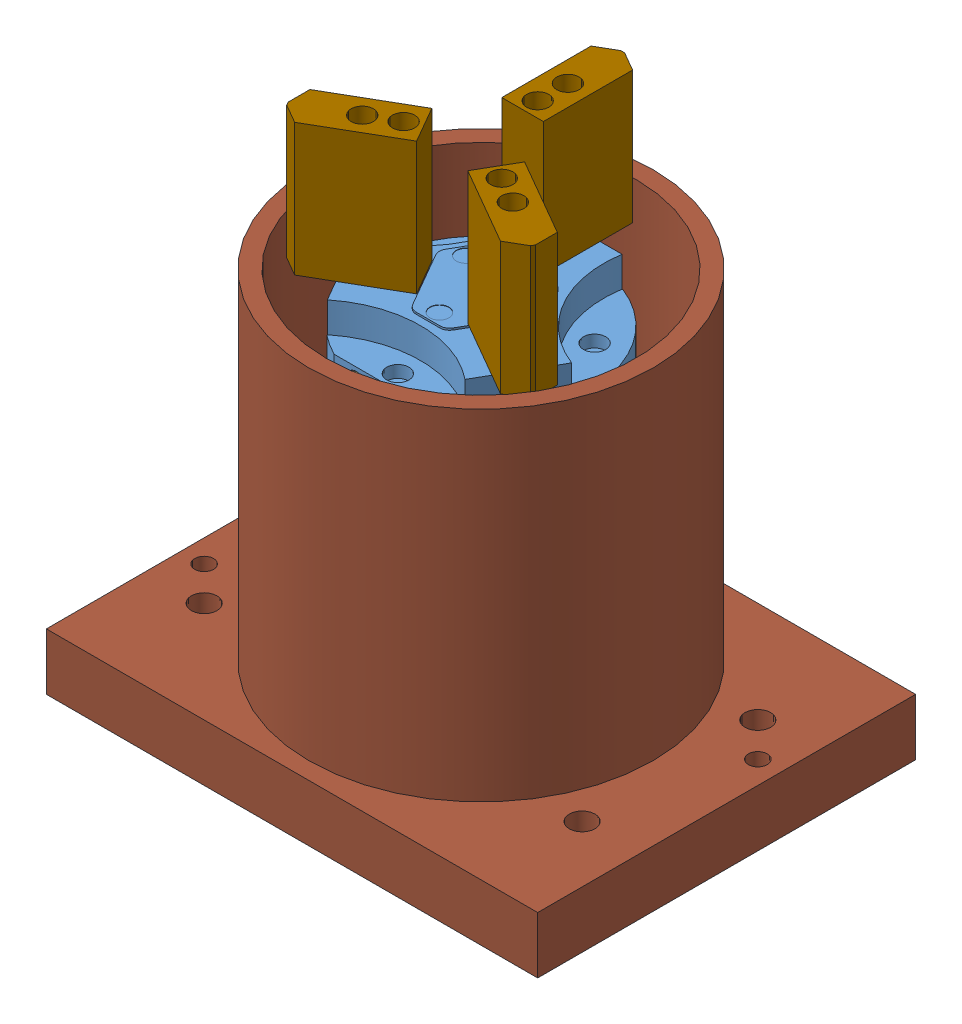
SolidWorks assembly Montagem_garra, configuration Default. Lengths in mm.
Overall size (130 138.12 100).
31 component instances, 12 part files, 72 mates.
Components (placement in the parent):
- 540862 HGDT-35-Az-1: 540862 HGDT-35-Az [Default] at origin size (58 45.5 53)
- 540862 HGDT-35-Aj-1: 540862 HGDT-35-Aj [Default] at (0 34 -2.7) x (0 0 -1) z (1 0 0) size (24.3 12 12)
- 540862 HGDT-35-Aj-2: 540862 HGDT-35-Aj [Default] at (2.3383 34 1.35) x (0.866025 0 0.5) z (-0.5 0 0.866025) size (24.3 12 12)
- 540862 HGDT-35-Aj-3: 540862 HGDT-35-Aj [Default] at (-2.3383 34 1.35) x (-0.866025 0 0.5) z (-0.5 0 -0.866025) size (24.3 12 12)
- DIN-913 - M5x5-1: DIN-913 - M5x5 [Default] at (-7 33.5 26) x (0 0 -1) z (-1 0 0) size (5.14 5 5)
- DIN-913 - M5x5-2: DIN-913 - M5x5 [Default] at (7 33.5 26) x (0 0 -1) z (-1 0 0) size (5.14 5 5)
- DIN-913 - M3x3-1: DIN-913 - M3x3 [Default] at (-7.5 0 18.5) x (0 1 0) z (-1 0 0) size (3.08 3 3)
- DIN-913 - M3x3-2: DIN-913 - M3x3 [Default] at (7.5 0 18.5) x (0 1 0) z (-1 0 0) size (3.08 3 3)
- Suporte_garra-1: Suporte_garra [Default] at (0 -10 0) x (-1 0 0) z (0 0 -1) size (85 10 85)
- parallel pin hardened_iso-1: parallel pin hardened_iso [ISO 8734 - 3 x 8 - A - St] at (-22.5 4 0) x (0 -1 0) z (-0.064733 0 -0.997903) size (8 3 3)
- parallel pin hardened_iso-2: parallel pin hardened_iso [ISO 8734 - 3 x 8 - A - St] at (22.5 4 0) x (0 -1 0) z (-0.052254 0 0.998634) size (8 3 3)
- socket head cap screw_iso-7: socket head cap screw_iso [ISO 4762 M4 x 10 - 10N] at (19.0526 -9.6 -11) x (0 1 0) z (0 0 1) size (14 7 7)
- socket head cap screw_iso-8: socket head cap screw_iso [ISO 4762 M4 x 10 - 10N] at (0 -9.6 22) x (0 1 0) z (0 0 1) size (14 7 7)
- socket head cap screw_iso-9: socket head cap screw_iso [ISO 4762 M4 x 10 - 10N] at (-19.0526 -9.6 -11) x (0 1 0) z (0 0 1) size (14 7 7)
- Centering_sleeve_8146543 ZBH-5-B-1: Centering_sleeve_8146543 ZBH-5-B [Default] at (-19.9186 47 11.5) x (0 -1 0) z (0.33337 0 0.942796) size (2.33 5 5.02)
- Centering_sleeve_8146543 ZBH-5-B-2: Centering_sleeve_8146543 ZBH-5-B [Default] at (-12.9904 47 7.5) x (0 -1 0) z (-0.239159 0 0.97098) size (2.33 5 5.02)
- Centering_sleeve_8146543 ZBH-5-B-7: Centering_sleeve_8146543 ZBH-5-B [Default] at (0 47 -23) x (0 -1 0) z (-0.800066 0 0.599912) size (2.33 5 5.02)
- Centering_sleeve_8146543 ZBH-5-B-8: Centering_sleeve_8146543 ZBH-5-B [Default] at (0 47 -15) x (0 -1 0) z (-0.813221 0 0.581954) size (2.33 5 5.02)
- Centering_sleeve_8146543 ZBH-5-B-9: Centering_sleeve_8146543 ZBH-5-B [Default] at (12.9904 47 7.5) x (0 -1 0) z (0.997447 0 -0.071406) size (2.33 5 5.02)
- Centering_sleeve_8146543 ZBH-5-B-10: Centering_sleeve_8146543 ZBH-5-B [Default] at (19.9186 47 11.5) x (0 -1 0) z (0.998302 0 0.058254) size (2.33 5 5.02)
- jaw_541102 BUB-HGDT-35---(P)-1: jaw_541102 BUB-HGDT-35---(P) [Default] at (-32.476 46 18.75) x (-0.5 0 -0.866025) z (0.866025 0 -0.5) size (11 35 26.5)
- jaw_541102 BUB-HGDT-35---(P)-2: jaw_541102 BUB-HGDT-35---(P) [Default] at (0 46 -37.5) size (11 35 26.5)
- jaw_541102 BUB-HGDT-35---(P)-3: jaw_541102 BUB-HGDT-35---(P) [Default] at (32.476 46 18.75) x (-0.5 0 0.866025) z (-0.866025 0 -0.5) size (11 35 26.5)
- socket head cap screw_din-2: socket head cap screw_din [DIN 912 M3 x 12 --- 12N] at (19.9186 55 11.5) x (0 -1 0) z (0 0 1) size (15 5.5 5.5)
- socket head cap screw_din-3: socket head cap screw_din [DIN 912 M3 x 12 --- 12N] at (12.9904 55 7.5) x (0 -1 0) z (0 0 1) size (15 5.5 5.5)
- socket head cap screw_din-4: socket head cap screw_din [DIN 912 M3 x 12 --- 12N] at (-12.9904 55 7.5) x (0 -1 0) z (0 0 1) size (15 5.5 5.5)
- socket head cap screw_din-5: socket head cap screw_din [DIN 912 M3 x 12 --- 12N] at (-19.9186 55 11.5) x (0 -1 0) z (0 0 1) size (15 5.5 5.5)
- socket head cap screw_din-6: socket head cap screw_din [DIN 912 M3 x 12 --- 12N] at (0 55 -15) x (0 -1 0) z (0 0 1) size (15 5.5 5.5)
- socket head cap screw_din-7: socket head cap screw_din [DIN 912 M3 x 12 --- 12N] at (0 55 -23) x (0 -1 0) z (0 0 1) size (15 5.5 5.5)
- Ponta_prensa-1: Ponta_prensa [Default] at (0 -55 0) size (130 105 100)
- mola_prensa-1: mola_prensa [Default] at (0 -55 0) size (82.36 49.25 81.45)
Mates (geometry in assembly coordinates):
- Coincident1: coincident anti-aligned: line of 540862 HGDT-35-Az-1 through (0 34 80.9) axis (0 0 -1); line of 540862 HGDT-35-Aj-1 through (0 34 -83.6) axis (0 0 1)
- Angle3: planar angle = 3.141593 rad aligned: plane of 540862 HGDT-35-Aj-1 through (0 34 -2.7) normal (-1 0 0); plane of 540862 HGDT-35-Az-1 through (0 0 0) normal (1 0 0)
- Coincident2: coincident aligned: line of 540862 HGDT-35-Az-1 through (70.0615 34 40.45) axis (-0.866025 0 -0.5); line of 540862 HGDT-35-Aj-2 through (72.3997 34 41.8) axis (-0.866025 0 -0.5)
- Angle6: planar angle = 0 rad aligned: plane of 540862 HGDT-35-Aj-2 through (2.3383 34 1.35) normal (0.5 0 -0.866025); plane of 540862 HGDT-35-Az-1 through (0 0 0) normal (0.5 0 -0.866025)
- Coincident3: coincident anti-aligned: line of 540862 HGDT-35-Az-1 through (70.0615 34 -40.45) axis (-0.866025 0 0.5); line of 540862 HGDT-35-Aj-3 through (-72.3997 34 41.8) axis (0.866025 0 -0.5)
- Angle9: planar angle = 3.141593 rad aligned: plane of 540862 HGDT-35-Aj-3 through (-2.3383 34 1.35) normal (0.5 0 0.866025); plane of 540862 HGDT-35-Az-1 through (0 0 0) normal (-0.5 0 -0.866025)
- Distance1: distance = 0 mm anti-aligned: plane of 540862 HGDT-35-Az-1 through (0 0 26) normal (0 0 1); plane of DIN-913 - M5x5-1 through (-7 33.5 26) normal (0 0 -1)
- Coincident4: coincident anti-aligned: line of 540862 HGDT-35-Az-1 through (-7 33.5 80.9) axis (0 0 -1); line of DIN-913 - M5x5-1 through (-7 33.5 -54.9) axis (0 0 1)
- Angle12: planar angle = 0 rad aligned: plane of DIN-913 - M5x5-1 through (-7 33.5 26) normal (1 0 0); plane of 540862 HGDT-35-Az-1 through (-7 0 0) normal (1 0 0)
- Distance2: distance = 0 mm anti-aligned: plane of 540862 HGDT-35-Az-1 through (0 0 26) normal (0 0 1); plane of DIN-913 - M5x5-2 through (7 33.5 26) normal (0 0 -1)
- Coincident5: coincident anti-aligned: line of 540862 HGDT-35-Az-1 through (7 33.5 80.9) axis (0 0 -1); line of DIN-913 - M5x5-2 through (7 33.5 -54.9) axis (0 0 1)
- Angle15: planar angle = 0 rad aligned: plane of DIN-913 - M5x5-2 through (7 33.5 26) normal (1 0 0); plane of 540862 HGDT-35-Az-1 through (7 0 0) normal (1 0 0)
- Distance3: distance = 0 mm anti-aligned: plane of 540862 HGDT-35-Az-1 through (0 0 0) normal (0 -1 0); plane of DIN-913 - M3x3-1 through (-7.5 0 18.5) normal (0 1 0)
- Coincident6: coincident anti-aligned: line of 540862 HGDT-35-Az-1 through (-7.5 -50 18.5) axis (0 1 0); line of DIN-913 - M3x3-1 through (-7.5 80.9 18.5) axis (0 -1 0)
- Angle18: planar angle = 0 rad aligned: plane of DIN-913 - M3x3-1 through (-7.5 0 18.5) normal (1 0 0); plane of 540862 HGDT-35-Az-1 through (-7.5 0 0) normal (1 0 0)
- Distance4: distance = 0 mm anti-aligned: plane of 540862 HGDT-35-Az-1 through (0 0 0) normal (0 -1 0); plane of DIN-913 - M3x3-2 through (7.5 0 18.5) normal (0 1 0)
- Coincident7: coincident anti-aligned: line of 540862 HGDT-35-Az-1 through (7.5 -50 18.5) axis (0 1 0); line of DIN-913 - M3x3-2 through (7.5 80.9 18.5) axis (0 -1 0)
- Angle21: planar angle = 0 rad aligned: plane of DIN-913 - M3x3-2 through (7.5 0 18.5) normal (1 0 0); plane of 540862 HGDT-35-Az-1 through (7.5 0 0) normal (1 0 0)
- LimitDistance1: limit distance = 0 mm anti-aligned: plane of 540862 HGDT-35-Aj-2 through (9.5263 34 5.5) normal (-0.866025 0 -0.5); plane of 540862 HGDT-35-Az-1 through (9.5263 0 5.5) normal (0.866025 0 0.5)
- LimitDistance2: limit distance = 0 mm anti-aligned: plane of 540862 HGDT-35-Az-1 through (-9.5263 0 5.5) normal (-0.866025 0 0.5); plane of 540862 HGDT-35-Aj-3 through (-9.5263 34 5.5) normal (0.866025 0 -0.5)
- LimitDistance3: limit distance = 0 mm anti-aligned: plane of 540862 HGDT-35-Az-1 through (0 0 -11) normal (0 0 -1); plane of 540862 HGDT-35-Aj-1 through (0 34 -11) normal (0 0 1)
- Concentric1: concentric aligned: cylinder of 540862 HGDT-35-Az-1 through (0 0 0) axis (0 -1 0) radius 12.5; cylinder of Suporte_garra-1 through (0 0 0) axis (0 -1 0) radius 42.5
- Concentric2: concentric anti-aligned: cylinder of 540862 HGDT-35-Az-1 through (22.5 0 0) axis (0 -1 0) radius 1.5; cylinder of Suporte_garra-1 through (22.5 -5 0) axis (0 1 0) radius 1.5
- Coincident8: coincident anti-aligned: plane of 540862 HGDT-35-Az-1 through (0 0 0) normal (0 -1 0); plane of Suporte_garra-1 through (0 0 0) normal (0 1 0)
- Concentric3: concentric anti-aligned: cylinder of 540862 HGDT-35-Az-1 through (22.5 0 0) axis (0 -1 0) radius 1.5; cylinder of parallel pin hardened_iso-2 through (22.5 10.35 0) axis (0 1 0) radius 1.5
- Concentric4: concentric anti-aligned: cylinder of 540862 HGDT-35-Az-1 through (-22.5 0 0) axis (0 -1 0) radius 1.5; cylinder of parallel pin hardened_iso-1 through (-22.5 10.35 0) axis (0 1 0) radius 1.5
- Distance5: distance = 1 mm anti-aligned: plane of 540862 HGDT-35-Az-1 through (-22.5 5 0) normal (0 -1 0); plane of parallel pin hardened_iso-1 through (-23.8632 4 0.0884) normal (0 1 0)
- Distance6: distance = 1 mm anti-aligned: plane of 540862 HGDT-35-Az-1 through (22.5 5 0) normal (0 -1 0); plane of parallel pin hardened_iso-2 through (23.8642 4 0.0714) normal (0 1 0)
- Concentric6: concentric anti-aligned: cylinder of Suporte_garra-1 through (19.0526 -10 -11) axis (0 1 0) radius 2.25; cylinder of socket head cap screw_iso-7 through (19.0526 -41.35 -11) axis (0 -1 0) radius 3.5
- Coincident12: coincident anti-aligned: plane of Suporte_garra-1 through (19.0526 -5.6 -11) normal (0 -1 0); plane of socket head cap screw_iso-7 through (15.5526 -5.6 -11) normal (0 1 0)
- Concentric7: concentric anti-aligned: cylinder of Suporte_garra-1 through (0 -10 22) axis (0 1 0) radius 2.25; cylinder of socket head cap screw_iso-8 through (0 -41.35 22) axis (0 -1 0) radius 3.5
- Coincident13: coincident anti-aligned: plane of Suporte_garra-1 through (0 -5.6 22) normal (0 -1 0); plane of socket head cap screw_iso-8 through (-3.5 -5.6 22) normal (0 1 0)
- Concentric8: concentric anti-aligned: cylinder of Suporte_garra-1 through (-19.0526 -10 -11) axis (0 1 0) radius 2.25; cylinder of socket head cap screw_iso-9 through (-19.0526 -41.35 -11) axis (0 -1 0) radius 3.5
- Coincident14: coincident anti-aligned: plane of Suporte_garra-1 through (-19.0526 -5.6 -11) normal (0 -1 0); plane of socket head cap screw_iso-9 through (-22.5526 -5.6 -11) normal (0 1 0)
- Concentric9: concentric anti-aligned: cylinder of 540862 HGDT-35-Aj-3 through (-19.9186 36.8401 11.5) axis (0 1 0) radius 1.2295; cylinder of Centering_sleeve_8146543 ZBH-5-B-1 through (-19.9186 44.7 11.5) axis (0 -1 0) radius 1.8
- Tangent1: tangent anti-aligned: plane of 540862 HGDT-35-Aj-3 through (-22.0836 44.7 12.75) normal (0 1 0); torus of Centering_sleeve_8146543 ZBH-5-B-1
- Concentric10: concentric anti-aligned: cylinder of 540862 HGDT-35-Aj-3 through (-12.9904 36.8401 7.5) axis (0 1 0) radius 2.5; cylinder of Centering_sleeve_8146543 ZBH-5-B-2 through (-12.9904 44.7 7.5) axis (0 -1 0) radius 2.5
- Tangent2: tangent anti-aligned: plane of 540862 HGDT-35-Aj-3 through (-15.1554 44.7 8.75) normal (0 1 0); torus of Centering_sleeve_8146543 ZBH-5-B-2
- Concentric15: concentric anti-aligned: cylinder of 540862 HGDT-35-Aj-1 through (0 36.8401 -23) axis (0 1 0) radius 2.5; cylinder of Centering_sleeve_8146543 ZBH-5-B-7 through (0 44.7 -23) axis (0 -1 0) radius 2.5
- Tangent3: tangent anti-aligned: plane of 540862 HGDT-35-Aj-1 through (0 44.7 -25.5) normal (0 1 0); torus of Centering_sleeve_8146543 ZBH-5-B-7
- Concentric16: concentric anti-aligned: cylinder of 540862 HGDT-35-Aj-1 through (0 36.8401 -15) axis (0 1 0) radius 2.5; cylinder of Centering_sleeve_8146543 ZBH-5-B-8 through (0 44.7 -15) axis (0 -1 0) radius 1.8
- Tangent4: tangent anti-aligned: plane of 540862 HGDT-35-Aj-1 through (0 44.7 -17.5) normal (0 1 0); torus of Centering_sleeve_8146543 ZBH-5-B-8
- Concentric17: concentric anti-aligned: cylinder of 540862 HGDT-35-Aj-2 through (12.9904 36.8401 7.5) axis (0 1 0) radius 2.5; cylinder of Centering_sleeve_8146543 ZBH-5-B-9 through (12.9904 44.7 7.5) axis (0 -1 0) radius 2.5
- Concentric18: concentric anti-aligned: cylinder of 540862 HGDT-35-Aj-2 through (19.9186 36.8401 11.5) axis (0 1 0) radius 2.5; cylinder of Centering_sleeve_8146543 ZBH-5-B-10 through (19.9186 44.7 11.5) axis (0 -1 0) radius 2.5
- Tangent5: tangent anti-aligned: plane of 540862 HGDT-35-Aj-2 through (15.1554 44.7 8.75) normal (0 1 0); torus of Centering_sleeve_8146543 ZBH-5-B-9
- Tangent6: tangent anti-aligned: plane of 540862 HGDT-35-Aj-2 through (22.0836 44.7 12.75) normal (0 1 0); torus of Centering_sleeve_8146543 ZBH-5-B-10
- Concentric19: concentric anti-aligned: circle of Centering_sleeve_8146543 ZBH-5-B-2; cylinder of jaw_541102 BUB-HGDT-35---(P)-1 through (-12.9904 46 7.5) axis (0 1 0) radius 2.95
- Concentric20: concentric anti-aligned: circle of Centering_sleeve_8146543 ZBH-5-B-1; cylinder of jaw_541102 BUB-HGDT-35---(P)-1 through (-19.9186 46 11.5) axis (0 1 0) radius 2.95
- Coincident15: coincident anti-aligned: plane of 540862 HGDT-35-Aj-3 through (-21.7577 46 16.3146) normal (0 1 0); plane of jaw_541102 BUB-HGDT-35---(P)-1 through (-32.476 46 18.75) normal (0 -1 0)
- Concentric21: concentric anti-aligned: circle of Centering_sleeve_8146543 ZBH-5-B-7; cylinder of jaw_541102 BUB-HGDT-35---(P)-2 through (0 46 -23) axis (0 1 0) radius 2.95
- Concentric22: concentric anti-aligned: circle of Centering_sleeve_8146543 ZBH-5-B-8; cylinder of jaw_541102 BUB-HGDT-35---(P)-2 through (0 46 -15) axis (0 1 0) radius 2.95
- Concentric23: concentric anti-aligned: circle of Centering_sleeve_8146543 ZBH-5-B-10; cylinder of jaw_541102 BUB-HGDT-35---(P)-3 through (19.9186 46 11.5) axis (0 1 0) radius 2.95
- Concentric24: concentric anti-aligned: circle of Centering_sleeve_8146543 ZBH-5-B-9; cylinder of jaw_541102 BUB-HGDT-35---(P)-3 through (12.9904 46 7.5) axis (0 1 0) radius 2.95
- Coincident16: coincident anti-aligned: plane of 540862 HGDT-35-Aj-1 through (-3.25 46 -27) normal (0 1 0); plane of jaw_541102 BUB-HGDT-35---(P)-2 through (0 46 -37.5) normal (0 -1 0)
- Coincident17: coincident anti-aligned: plane of 540862 HGDT-35-Aj-2 through (25.0077 46 10.6854) normal (0 1 0); plane of jaw_541102 BUB-HGDT-35---(P)-3 through (32.476 46 18.75) normal (0 -1 0)
- Concentric25: concentric aligned: cylinder of jaw_541102 BUB-HGDT-35---(P)-3 through (19.9186 46 11.5) axis (0 1 0) radius 1.6; cylinder of socket head cap screw_din-2 through (19.9186 86.75 11.5) axis (0 1 0) radius 2.75
- Coincident18: coincident anti-aligned: plane of jaw_541102 BUB-HGDT-35---(P)-3 through (22.4734 52 12.975) normal (0 1 0); plane of socket head cap screw_din-2 through (22.6686 52 11.5) normal (0 -1 0)
- Concentric26: concentric aligned: cylinder of jaw_541102 BUB-HGDT-35---(P)-3 through (12.9904 46 7.5) axis (0 1 0) radius 2.95; cylinder of socket head cap screw_din-3 through (12.9904 86.75 7.5) axis (0 1 0) radius 2.75
- Coincident19: coincident anti-aligned: plane of jaw_541102 BUB-HGDT-35---(P)-3 through (15.5452 52 8.975) normal (0 1 0); plane of socket head cap screw_din-3 through (15.7404 52 7.5) normal (0 -1 0)
- Concentric27: concentric aligned: cylinder of jaw_541102 BUB-HGDT-35---(P)-1 through (-12.9904 46 7.5) axis (0 1 0) radius 2.95; cylinder of socket head cap screw_din-4 through (-12.9904 86.75 7.5) axis (0 1 0) radius 2.75
- Coincident20: coincident anti-aligned: plane of jaw_541102 BUB-HGDT-35---(P)-1 through (-15.5452 52 8.975) normal (0 1 0); plane of socket head cap screw_din-4 through (-10.2404 52 7.5) normal (0 -1 0)
- Concentric28: concentric aligned: cylinder of jaw_541102 BUB-HGDT-35---(P)-1 through (-19.9186 46 11.5) axis (0 1 0) radius 1.6; cylinder of socket head cap screw_din-5 through (-19.9186 86.75 11.5) axis (0 1 0) radius 2.75
- Coincident21: coincident anti-aligned: plane of jaw_541102 BUB-HGDT-35---(P)-1 through (-22.4734 52 12.975) normal (0 1 0); plane of socket head cap screw_din-5 through (-17.1686 52 11.5) normal (0 -1 0)
- Concentric29: concentric aligned: cylinder of jaw_541102 BUB-HGDT-35---(P)-2 through (0 46 -15) axis (0 1 0) radius 2.95; cylinder of socket head cap screw_din-6 through (0 86.75 -15) axis (0 1 0) radius 2.75
- Coincident22: coincident anti-aligned: plane of jaw_541102 BUB-HGDT-35---(P)-2 through (0 52 -17.95) normal (0 1 0); plane of socket head cap screw_din-6 through (2.75 52 -15) normal (0 -1 0)
- Concentric30: concentric aligned: cylinder of jaw_541102 BUB-HGDT-35---(P)-2 through (0 46 -23) axis (0 1 0) radius 2.95; cylinder of socket head cap screw_din-7 through (0 86.75 -23) axis (0 1 0) radius 2.75
- Coincident23: coincident anti-aligned: plane of jaw_541102 BUB-HGDT-35---(P)-2 through (0 52 -25.95) normal (0 1 0); plane of socket head cap screw_din-7 through (2.75 52 -23) normal (0 -1 0)
- Concentric31: concentric aligned: cylinder of Suporte_garra-1 through (0 0 0) axis (0 -1 0) radius 42.5; cylinder of Ponta_prensa-1 through (0 0 0) axis (0 -1 0) radius 42.5
- LimitDistance4: limit distance = 0 mm anti-aligned: plane of Suporte_garra-1 through (0 0 0) normal (0 1 0); plane of Ponta_prensa-1 through (0 0 0) normal (0 -1 0)
- Concentric32: concentric anti-aligned: cylinder of Ponta_prensa-1 through (0 0 0) axis (0 -1 0) radius 42.5; circle of mola_prensa-1
- Coincident24: coincident anti-aligned: plane of Suporte_garra-1 through (0 -10 0) normal (0 -1 0); plane of mola_prensa-1 through (0 -10 0) normal (0 1 0)
- Parallel1: parallel aligned: plane of Ponta_prensa-1 through (-65 -40 50) normal (0 0 1)
